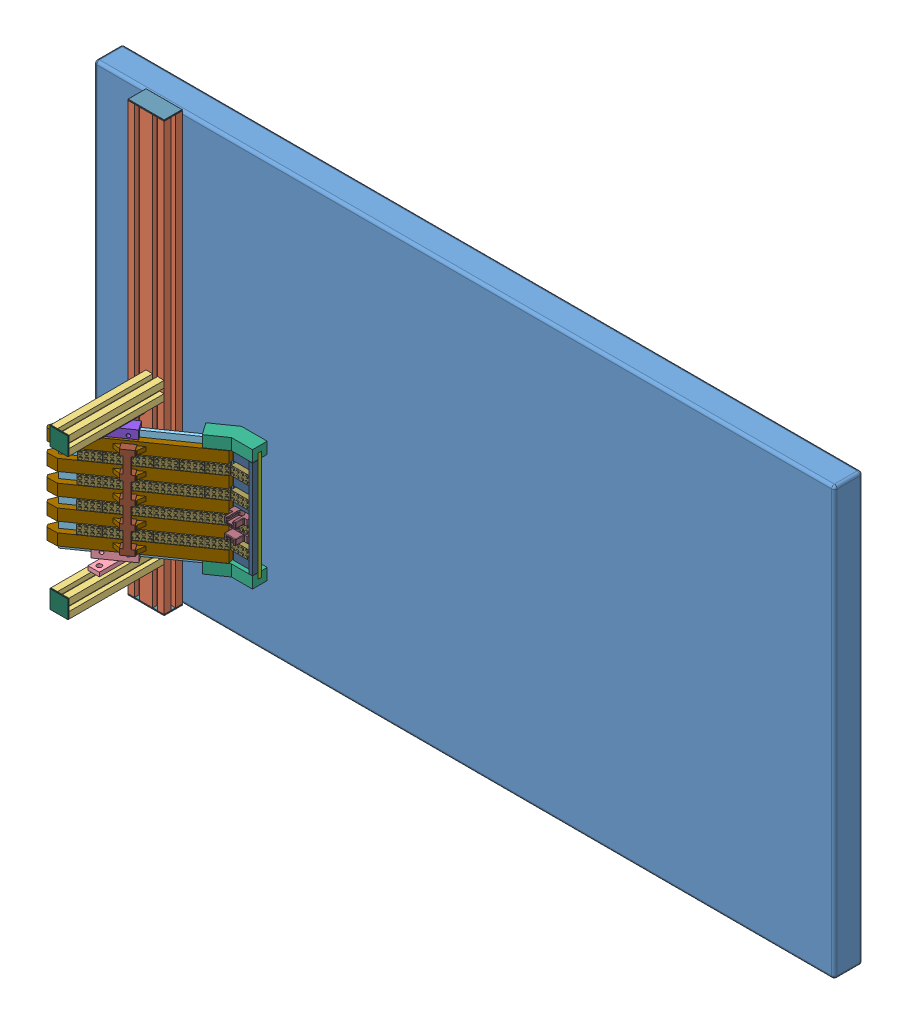
SolidWorks assembly Magazin_komplett, configuration Standard. Lengths in mm.
Overall size (1300 754 250.8).
54 component instances, 16 part files, 118 mates.
Components (placement in the parent):
- Tischplatte-1: Tischplatte [Standard] at (82.6175 27.9833 1300) size (1300 750 50)
- Bosch_Schiene-1: Bosch_Schiene [Standard] at (-444.1514 -347.0167 1381.8) x (1 0 0) z (0 1 0) size (63.6 31.8 750)
- Stützpfeiler-1: Stützpfeiler [Standard] at (-444.1514 -270.5414 1381.8) size (31.8 31.8 167)
- Adapter_Stütze_Magazin-1: Adapter_Stütze_Magazin [Standard] at (-438.2514 -238.7414 1489.7538) x (1 0 0) z (0 1 0) size (60.62 80 22)
- Holzplatte-1: Holzplatte [Standard] at (-485.6098 -226.7414 1493.64) x (0 1 0) z (-0.819152 0 0.573576) size (192 6 220)
- Winkel-1: Winkel [Standard] at (-273.1782 -226.7414 1360) x (-1 0 0) z (0 1 0) size (81.89 47.03 20)
- Holzplatte_kurz-1: Holzplatte_kurz [Standard] at (-303.1782 -226.7414 1365.9) x (0 1 0) z (-1 0 0) size (192 6 40)
- Winkel-2: Winkel [Standard] at (-331.1369 -34.7414 1378.2743) x (0.819152 0 -0.573576) z (0 -1 0) size (81.89 47.03 20)
- Adapter_Stütze_Magazin_gespiegelt-1: Adapter_Stütze_Magazin_gespiegelt [Standard] at (-438.2514 -22.7414 1409.8759) x (1 0 0) z (0 -1 0) size (60.62 80 22)
- Stützpfeiler-2: Stützpfeiler [Standard] at (-444.1514 -22.7414 1381.8) size (31.8 31.8 167)
- Schienen-1: Schienen [Standard] at (-485.6098 -196.5447 1493.64) x (0.819152 0 -0.573576) z (-0.573576 0 -0.819152) size (235 20 37.9)
- Schienen-2: Schienen [Standard] at (-485.6098 -158.7447 1493.64) x (0.819152 0 -0.573576) z (-0.573576 0 -0.819152) size (235 20 37.9)
- Schienen-3: Schienen [Standard] at (-485.6098 -120.9447 1493.64) x (0.819152 0 -0.573576) z (-0.573576 0 -0.819152) size (235 20 37.9)
- Schienen-4: Schienen [Standard] at (-485.6098 -83.1447 1493.64) x (0.819152 0 -0.573576) z (-0.573576 0 -0.819152) size (235 20 37.9)
- Schienen-5: Schienen [Standard] at (-485.6098 -45.3447 1493.64) x (0.819152 0 -0.573576) z (-0.573576 0 -0.819152) size (235 20 37.9)
- Entnahme_Kamm-1: Entnahme_Kamm [Standard] at (-263.1782 -216.5447 1365.9) x (0 1 0) z (1 0 0) size (171.2 10 40)
- Abstandshalter-1: Abstandshalter [Standard] at (-390.0599 -51.2247 1455.0572) x (0 -1 0) z (0.819152 0 -0.573576) size (161.32 13.2 20)
- GreiferMitLegostein-1: GreiferMitLegostein [Standard] at (-275.4934 -166.3532 1407.2912) x (0 0 -1) z (0 1 0) size (27.6 32 35.8)
  - Legostein-1: Legostein [Standard] at (41.3912 -5.9152 7.6084) x (0 1 0) z (0 0 1) size (31.8 11.4 15.8)
  - Greifbacken-2: Greifbacken [Standard] at (13.7912 20.1083 33.4084) x (1 0 0) z (0 0 -1) size (25.5 32 13.51) (hidden)
  - Greifbacken-3: Greifbacken [Standard] at (13.7912 -0.0917 -2.3916) size (25.5 32 13.51) (hidden)
  - Greifbacken_HSHL-1: Greifbacken_HSHL [Standard] at (13.7912 -0.2152 -2.3916) size (24.5 32 13.51)
  - Greifbacken_HSHL-2: Greifbacken_HSHL [Standard] at (13.7912 19.9848 33.4084) x (1 0 0) z (0 0 -1) size (24.5 32 13.51)
- Legostein-2: Legostein [Standard] at (-269.5782 -196.5447 1365.9) x (-1 0 0) z (0 1 0) size (31.8 11.4 15.8)
- Legostein-4: Legostein [Standard] at (-269.5782 -120.9447 1365.9) x (-1 0 0) z (0 1 0) size (31.8 11.4 15.8)
- Legostein-5: Legostein [Standard] at (-269.5782 -83.1447 1365.9) x (-1 0 0) z (0 1 0) size (31.8 11.4 15.8)
- Legostein-6: Legostein [Standard] at (-360.206 -196.5447 1405.8313) x (-0.819152 0 0.573576) z (0 1 0) size (31.8 11.4 15.8)
- Legostein-7: Legostein [Standard] at (-439.6163 -196.5447 1461.435) x (-0.819152 0 0.573576) z (0 1 0) size (31.8 11.4 15.8)
- Legostein-8: Legostein [Standard] at (-386.6114 -196.5447 1424.3206) x (-0.819152 0 0.573576) z (0 1 0) size (31.8 11.4 15.8)
- Legostein-9: Legostein [Standard] at (-307.4942 -196.5447 1368.9221) x (-0.819152 0 0.573576) z (0 1 0) size (31.8 11.4 15.8)
- Legostein-10: Legostein [Standard] at (-413.1818 -196.5447 1442.9253) x (-0.819152 0 0.573576) z (0 1 0) size (31.8 11.4 15.8)
- Legostein-11: Legostein [Standard] at (-333.8754 -196.5447 1387.3944) x (-0.819152 0 0.573576) z (0 1 0) size (31.8 11.4 15.8)
- Legostein-12: Legostein [Standard] at (-307.4185 -158.7447 1368.8691) x (-0.819152 0 0.573576) z (0 1 0) size (31.8 11.4 15.8)
- Legostein-13: Legostein [Standard] at (-333.8419 -158.7447 1387.371) x (-0.819152 0 0.573576) z (0 1 0) size (31.8 11.4 15.8)
- Legostein-14: Legostein [Standard] at (-360.1564 -158.7447 1405.7966) x (-0.819152 0 0.573576) z (0 1 0) size (31.8 11.4 15.8)
- Legostein-15: Legostein [Standard] at (-386.5305 -158.7447 1424.2639) x (-0.819152 0 0.573576) z (0 1 0) size (31.8 11.4 15.8)
- Legostein-16: Legostein [Standard] at (-413.0944 -158.7447 1442.8642) x (-0.819152 0 0.573576) z (0 1 0) size (31.8 11.4 15.8)
- Legostein-17: Legostein [Standard] at (-439.591 -158.7447 1461.4173) x (-0.819152 0 0.573576) z (0 1 0) size (31.8 11.4 15.8)
- Legostein-18: Legostein [Standard] at (-439.252 -120.9447 1461.1799) x (-0.819152 0 0.573576) z (0 1 0) size (31.8 11.4 15.8)
- Legostein-19: Legostein [Standard] at (-412.8102 -120.9447 1442.6651) x (-0.819152 0 0.573576) z (0 1 0) size (31.8 11.4 15.8)
- Legostein-20: Legostein [Standard] at (-386.5116 -120.9447 1424.2507) x (-0.819152 0 0.573576) z (0 1 0) size (31.8 11.4 15.8)
- Legostein-21: Legostein [Standard] at (-360.154 -120.9447 1405.7949) x (-0.819152 0 0.573576) z (0 1 0) size (31.8 11.4 15.8)
- Legostein-22: Legostein [Standard] at (-333.7719 -120.9447 1387.3219) x (-0.819152 0 0.573576) z (0 1 0) size (31.8 11.4 15.8)
- Legostein-23: Legostein [Standard] at (-307.3652 -120.9447 1368.8318) x (-0.819152 0 0.573576) z (0 1 0) size (31.8 11.4 15.8)
- Legostein-24: Legostein [Standard] at (-307.2324 -83.1447 1368.7388) x (-0.819152 0 0.573576) z (0 1 0) size (31.8 11.4 15.8)
- Legostein-25: Legostein [Standard] at (-412.5918 -83.1447 1442.5123) x (-0.819152 0 0.573576) z (0 1 0) size (31.8 11.4 15.8)
- Legostein-26: Legostein [Standard] at (-386.1974 -83.1447 1424.0307) x (-0.819152 0 0.573576) z (0 1 0) size (31.8 11.4 15.8)
- Legostein-27: Legostein [Standard] at (-359.8901 -83.1447 1405.6101) x (-0.819152 0 0.573576) z (0 1 0) size (31.8 11.4 15.8)
- Legostein-28: Legostein [Standard] at (-333.5713 -83.1447 1387.1815) x (-0.819152 0 0.573576) z (0 1 0) size (31.8 11.4 15.8)
- Legostein-29: Legostein [Standard] at (-438.9743 -83.1447 1460.9854) x (-0.819152 0 0.573576) z (0 1 0) size (31.8 11.4 15.8)
- Abdeckung_Breit-1: Abdeckung_Breit [Standard] at (-444.1514 -349.0167 1365.9) x (1 0 0) z (0 1 0) size (63.6 31.8 2)
- Abdeckung_Breit-2: Abdeckung_Breit [Standard] at (-444.1514 402.9833 1365.9) x (1 0 0) z (0 1 0) size (63.6 31.8 2)
- Abdeckung_quadratisch-1: Abdeckung_quadratisch [Standard] at (-428.2514 -254.6414 1548.8) size (31.8 31.8 2)
- Abdeckung_quadratisch-2: Abdeckung_quadratisch [Standard] at (-428.2514 -6.8414 1548.8) size (31.8 31.8 2)
Mates (geometry in assembly coordinates):
- Deckungsgleich1: coincident anti-aligned: plane of Tischplatte-1 through (82.6175 27.9833 1350) normal (0 0 1); plane of Bosch_Schiene-1 through (-444.1514 402.9833 1350) normal (0 0 -1)
- Deckungsgleich2: coincident aligned: plane of Tischplatte-1 through (-567.3825 402.9833 1350) normal (0 1 0); plane of Bosch_Schiene-1 through (-444.1514 402.9833 1381.8) normal (0 1 0)
- Deckungsgleich3: coincident anti-aligned: plane of Bosch_Schiene-1 through (-444.1514 402.9833 1381.8) normal (0 0 1); plane of Stützpfeiler-1 through (-444.1514 -270.5414 1381.8) normal (0 0 -1)
- Parallel1: parallel aligned: line of Bosch_Schiene-1 through (-432.5514 -347.0167 1374) axis (1 0 0); line of Stützpfeiler-1 through (-432.5514 -262.7414 1381.8) axis (1 0 0)
- Deckungsgleich6: coincident anti-aligned: line of Bosch_Schiene-1 through (-412.3514 402.9833 1381.8) axis (0 -1 0); line of Stützpfeiler-1 through (-412.3514 -270.5414 1381.8) axis (0 1 0)
- Deckungsgleich7: coincident anti-aligned: plane of Stützpfeiler-1 through (-444.1514 -238.7414 1548.8) normal (0 1 0); plane of Adapter_Stütze_Magazin-1 through (-438.2514 -238.7414 1489.7538) normal (0 -1 0)
- Tangential1: tangent anti-aligned: plane of Stützpfeiler-1 through (-432.5514 -238.7414 1548.8) normal (1 0 0); cylinder of Adapter_Stütze_Magazin-1 through (-428.2514 -231.7414 1479.7538) axis (0 -1 0) radius 4.3
- Tangential2: tangent anti-aligned: plane of Stützpfeiler-1 through (-432.5514 -238.7414 1548.8) normal (1 0 0); cylinder of Adapter_Stütze_Magazin-1 through (-428.2514 -231.7414 1419.7538) axis (0 -1 0) radius 4.3
- Deckungsgleich9: coincident anti-aligned: plane of Adapter_Stütze_Magazin-1 through (-438.2514 -226.7414 1489.7538) normal (0 1 0); plane of Holzplatte-1 through (-489.0512 -226.7414 1488.725) normal (0 -1 0)
- Deckungsgleich10: coincident anti-aligned: plane of Adapter_Stütze_Magazin-1 through (-405.3689 -226.7414 1430.13) normal (0.573576 0 0.819152); plane of Holzplatte-1 through (-489.0512 -226.7414 1488.725) normal (-0.573576 0 -0.819152)
- Deckungsgleich11: coincident anti-aligned: plane of Holzplatte-1 through (-489.0512 -226.7414 1488.725) normal (0 -1 0); plane of Winkel-1 through (-273.1782 -226.7414 1360) normal (0 1 0)
- Deckungsgleich12: coincident anti-aligned: plane of Holzplatte-1 through (-485.6098 -226.7414 1493.64) normal (0.573576 0 0.819152); plane of Winkel-1 through (-280.2758 -216.7414 1349.8636) normal (-0.573576 0 -0.819152)
- Deckungsgleich13: coincident anti-aligned: plane of Winkel-1 through (-273.1782 -226.7414 1360) normal (0 1 0); plane of Holzplatte_kurz-1 through (-303.1782 -226.7414 1359.9) normal (0 -1 0)
- Deckungsgleich14: coincident anti-aligned: plane of Winkel-1 through (-273.1782 -216.7414 1365.9) normal (0 0 -1); plane of Holzplatte_kurz-1 through (-303.1782 -226.7414 1365.9) normal (0 0 1)
- Deckungsgleich15: coincident aligned: plane of Winkel-1 through (-263.1782 -216.7414 1360) normal (1 0 0); plane of Holzplatte_kurz-1 through (-263.1782 -226.7414 1359.9) normal (1 0 0)
- Deckungsgleich16: coincident anti-aligned: plane of Holzplatte-1 through (-489.0512 -34.7414 1488.725) normal (0 1 0); plane of Winkel-2 through (-331.1369 -34.7414 1378.2743) normal (0 -1 0)
- Deckungsgleich17: coincident anti-aligned: plane of Holzplatte-1 through (-485.6098 -226.7414 1493.64) normal (0.573576 0 0.819152); plane of Winkel-2 through (-327.7528 -44.7414 1383.1073) normal (-0.573576 0 -0.819152)
- Deckungsgleich18: coincident anti-aligned: plane of Holzplatte_kurz-1 through (-303.1782 -226.7414 1365.9) normal (0 0 1); plane of Winkel-2 through (-331.1369 -44.7414 1365.9) normal (0 0 -1)
- Deckungsgleich19: coincident anti-aligned: plane of Tischplatte-1 through (82.6175 27.9833 1350) normal (0 0 1); plane of Winkel-1 through (-273.1782 -236.7414 1350) normal (0 0 -1)
- Deckungsgleich20: coincident anti-aligned: plane of Holzplatte-1 through (-489.0512 -34.7414 1488.725) normal (0 1 0); plane of Adapter_Stütze_Magazin_gespiegelt-1 through (-438.2514 -34.7414 1409.8759) normal (0 -1 0)
- Deckungsgleich21: coincident anti-aligned: plane of Holzplatte-1 through (-485.6098 -226.7414 1493.64) normal (0.573576 0 0.819152); plane of Adapter_Stütze_Magazin_gespiegelt-1 through (-401.9848 -34.7414 1435.0851) normal (-0.573576 0 -0.819152)
- Deckungsgleich22: coincident aligned: plane of Adapter_Stütze_Magazin-1 through (-418.2514 -231.7414 1489.7538) normal (1 0 0); plane of Adapter_Stütze_Magazin_gespiegelt-1 through (-418.2514 -29.7414 1409.8759) normal (1 0 0)
- Deckungsgleich23: coincident anti-aligned: plane of Bosch_Schiene-1 through (-444.1514 402.9833 1381.8) normal (0 0 1); plane of Stützpfeiler-2 through (-444.1514 -22.7414 1381.8) normal (0 0 -1)
- Deckungsgleich24: coincident aligned: plane of Bosch_Schiene-1 through (-412.3514 402.9833 1381.8) normal (1 0 0); plane of Stützpfeiler-2 through (-412.3514 -11.1414 1548.8) normal (1 0 0)
- Deckungsgleich25: coincident anti-aligned: plane of Adapter_Stütze_Magazin_gespiegelt-1 through (-438.2514 -22.7414 1409.8759) normal (0 1 0); plane of Stützpfeiler-2 through (-423.9514 -22.7414 1548.8) normal (0 -1 0)
- Deckungsgleich26: coincident anti-aligned: plane of Holzplatte-1 through (-485.6098 -226.7414 1493.64) normal (0.573576 0 0.819152); plane of Schienen-1 through (-485.6098 -216.5447 1493.64) normal (-0.573576 0 -0.819152)
- Deckungsgleich27: coincident anti-aligned: plane of Holzplatte-1 through (-489.0512 -226.7414 1488.725) normal (-0.819152 0 0.573576); plane of Schienen-1 through (-485.6098 -216.5447 1493.64) normal (0.819152 0 -0.573576)
- Deckungsgleich28: coincident anti-aligned: plane of Holzplatte-1 through (-485.6098 -226.7414 1493.64) normal (0.573576 0 0.819152); plane of Schienen-2 through (-485.6098 -178.7447 1493.64) normal (-0.573576 0 -0.819152)
- Deckungsgleich29: coincident anti-aligned: plane of Holzplatte-1 through (-485.6098 -226.7414 1493.64) normal (0.573576 0 0.819152); plane of Schienen-3 through (-485.6098 -140.9447 1493.64) normal (-0.573576 0 -0.819152)
- Deckungsgleich30: coincident anti-aligned: plane of Holzplatte-1 through (-485.6098 -226.7414 1493.64) normal (0.573576 0 0.819152); plane of Schienen-4 through (-485.6098 -103.1447 1493.64) normal (-0.573576 0 -0.819152)
- Deckungsgleich31: coincident anti-aligned: plane of Holzplatte-1 through (-485.6098 -226.7414 1493.64) normal (0.573576 0 0.819152); plane of Schienen-5 through (-485.6098 -65.3447 1493.64) normal (-0.573576 0 -0.819152)
- Deckungsgleich32: coincident anti-aligned: plane of Holzplatte-1 through (-489.0512 -226.7414 1488.725) normal (-0.819152 0 0.573576); plane of Schienen-2 through (-485.6098 -178.7447 1493.64) normal (0.819152 0 -0.573576)
- Deckungsgleich33: coincident anti-aligned: plane of Holzplatte-1 through (-489.0512 -226.7414 1488.725) normal (-0.819152 0 0.573576); plane of Schienen-3 through (-485.6098 -140.9447 1493.64) normal (0.819152 0 -0.573576)
- Deckungsgleich34: coincident anti-aligned: plane of Holzplatte-1 through (-489.0512 -226.7414 1488.725) normal (-0.819152 0 0.573576); plane of Schienen-4 through (-485.6098 -103.1447 1493.64) normal (0.819152 0 -0.573576)
- Deckungsgleich35: coincident anti-aligned: plane of Holzplatte-1 through (-489.0512 -226.7414 1488.725) normal (-0.819152 0 0.573576); plane of Schienen-5 through (-485.6098 -65.3447 1493.64) normal (0.819152 0 -0.573576)
- Deckungsgleich36: coincident anti-aligned: plane of Holzplatte_kurz-1 through (-303.1782 -226.7414 1365.9) normal (0 0 1); plane of Entnahme_Kamm-1 through (-263.1782 -216.5447 1365.9) normal (0 0 -1)
- Deckungsgleich37: coincident aligned: plane of Holzplatte_kurz-1 through (-263.1782 -226.7414 1359.9) normal (1 0 0); plane of Entnahme_Kamm-1 through (-263.1782 -216.5447 1368.9) normal (1 0 0)
- Deckungsgleich43: coincident aligned: plane of Schienen-1 through (-485.6098 -196.5447 1493.64) normal (0 1 0); plane of Entnahme_Kamm-1 through (-263.1782 -196.5447 1368.9) normal (0 1 0)
- Deckungsgleich44: coincident anti-aligned: plane of Schienen-1 through (-474.1382 -216.5447 1510.023) normal (0.573576 0 0.819152); plane of Abstandshalter-1 through (-391.8954 -51.2247 1452.4359) normal (-0.573576 0 -0.819152)
- Deckungsgleich45: coincident anti-aligned: plane of Schienen-1 through (-390.7482 -210.1447 1454.0742) normal (-0.819152 0 0.573576); plane of Abstandshalter-1 through (-391.8954 -51.2247 1452.4359) normal (0.819152 0 -0.573576)
- Deckungsgleich46: coincident anti-aligned: plane of Schienen-1 through (-485.6098 -210.1447 1493.64) normal (0 -1 0); plane of Abstandshalter-1 through (-397.6311 -210.1447 1444.2444) normal (0 1 0)
- Deckungsgleich47: coincident anti-aligned: plane of Schienen-2 through (-485.6098 -172.3447 1493.64) normal (0 -1 0); plane of Abstandshalter-1 through (-397.6311 -172.3447 1444.2444) normal (0 1 0)
- Deckungsgleich48: coincident anti-aligned: plane of Schienen-3 through (-485.6098 -134.5447 1493.64) normal (0 -1 0); plane of Abstandshalter-1 through (-397.6311 -134.5447 1444.2444) normal (0 1 0)
- Deckungsgleich49: coincident anti-aligned: plane of Schienen-4 through (-485.6098 -96.7447 1493.64) normal (0 -1 0); plane of Abstandshalter-1 through (-414.0142 -96.7447 1455.7159) normal (0 1 0)
- Deckungsgleich50: coincident anti-aligned: plane of Schienen-5 through (-485.6098 -58.9447 1493.64) normal (0 -1 0); plane of Abstandshalter-1 through (-397.6311 -58.9447 1444.2444) normal (0 1 0)
- Deckungsgleich51: coincident anti-aligned: plane of Holzplatte_kurz-1 through (-303.1782 -226.7414 1365.9) normal (0 0 1); plane of GreiferMitLegostein-1/Legostein-1 through (-269.5782 -142.9447 1365.9) normal (0 0 -1)
- Deckungsgleich52: coincident anti-aligned: plane of Entnahme_Kamm-1 through (-269.5782 -216.5447 1368.9) normal (-1 0 0); plane of GreiferMitLegostein-1/Legostein-1 through (-269.5782 -142.9447 1365.9) normal (1 0 0)
- Deckungsgleich53: coincident anti-aligned: plane of Entnahme_Kamm-1 through (-263.1782 -158.7447 1368.9) normal (0 1 0); plane of GreiferMitLegostein-1/Legostein-1 through (-269.5782 -158.7447 1365.9) normal (0 -1 0)
- Deckungsgleich54: coincident anti-aligned: plane of Holzplatte_kurz-1 through (-303.1782 -226.7414 1365.9) normal (0 0 1); plane of Legostein-2 through (-269.5782 -180.7447 1365.9) normal (0 0 -1)
- Deckungsgleich55: coincident anti-aligned: plane of Entnahme_Kamm-1 through (-269.5782 -216.5447 1368.9) normal (-1 0 0); plane of Legostein-2 through (-269.5782 -180.7447 1365.9) normal (1 0 0)
- Deckungsgleich56: coincident anti-aligned: plane of Entnahme_Kamm-1 through (-263.1782 -196.5447 1368.9) normal (0 1 0); plane of Legostein-2 through (-269.5782 -196.5447 1365.9) normal (0 -1 0)
- Deckungsgleich57: coincident anti-aligned: plane of Holzplatte_kurz-1 through (-303.1782 -226.7414 1365.9) normal (0 0 1); plane of Legostein-4 through (-269.5782 -105.1447 1365.9) normal (0 0 -1)
- Deckungsgleich58: coincident anti-aligned: plane of Entnahme_Kamm-1 through (-269.5782 -216.5447 1368.9) normal (-1 0 0); plane of Legostein-4 through (-269.5782 -105.1447 1365.9) normal (1 0 0)
- Deckungsgleich59: coincident anti-aligned: plane of Entnahme_Kamm-1 through (-263.1782 -120.9447 1368.9) normal (0 1 0); plane of Legostein-4 through (-269.5782 -120.9447 1365.9) normal (0 -1 0)
- Deckungsgleich60: coincident anti-aligned: plane of Holzplatte_kurz-1 through (-303.1782 -226.7414 1365.9) normal (0 0 1); plane of Legostein-5 through (-269.5782 -67.3447 1365.9) normal (0 0 -1)
- Deckungsgleich61: coincident anti-aligned: plane of Entnahme_Kamm-1 through (-263.1782 -83.1447 1368.9) normal (0 1 0); plane of Legostein-5 through (-269.5782 -83.1447 1365.9) normal (0 -1 0)
- Deckungsgleich62: coincident anti-aligned: plane of Entnahme_Kamm-1 through (-269.5782 -216.5447 1368.9) normal (-1 0 0); plane of Legostein-5 through (-269.5782 -67.3447 1365.9) normal (1 0 0)
- Deckungsgleich63: coincident aligned: plane of Legostein-6 through (-360.206 -180.7447 1405.8313) normal (-0.573576 0 -0.819152); plane of Legostein-7 through (-439.6163 -180.7447 1461.435) normal (-0.573576 0 -0.819152)
- Deckungsgleich64: coincident aligned: plane of Legostein-6 through (-360.206 -180.7447 1405.8313) normal (-0.573576 0 -0.819152); plane of Legostein-7 through (-439.6163 -180.7447 1461.435) normal (-0.573576 0 -0.819152)
- Deckungsgleich65: coincident aligned: plane of Legostein-7 through (-439.6163 -180.7447 1461.435) normal (-0.573576 0 -0.819152); plane of Legostein-8 through (-386.6114 -180.7447 1424.3206) normal (-0.573576 0 -0.819152)
- Deckungsgleich66: coincident aligned: plane of Legostein-8 through (-386.6114 -180.7447 1424.3206) normal (-0.573576 0 -0.819152); plane of Legostein-9 through (-307.4942 -180.7447 1368.9221) normal (-0.573576 0 -0.819152)
- Deckungsgleich67: coincident aligned: plane of Legostein-9 through (-307.4942 -180.7447 1368.9221) normal (-0.573576 0 -0.819152); plane of Legostein-10 through (-413.1818 -180.7447 1442.9253) normal (-0.573576 0 -0.819152)
- Deckungsgleich68: coincident aligned: plane of Legostein-10 through (-413.1818 -180.7447 1442.9253) normal (-0.573576 0 -0.819152); plane of Legostein-11 through (-333.8754 -180.7447 1387.3944) normal (-0.573576 0 -0.819152)
- Deckungsgleich69: coincident anti-aligned: plane of Holzplatte-1 through (-485.6098 -226.7414 1493.64) normal (0.573576 0 0.819152); plane of Legostein-6 through (-360.206 -180.7447 1405.8313) normal (-0.573576 0 -0.819152)
- Deckungsgleich70: coincident aligned: plane of Legostein-6 through (-360.206 -196.5447 1405.8313) normal (0 -1 0); plane of Legostein-11 through (-333.8754 -196.5447 1387.3944) normal (0 -1 0)
- Deckungsgleich71: coincident aligned: plane of Legostein-6 through (-360.206 -196.5447 1405.8313) normal (0 -1 0); plane of Legostein-10 through (-413.1818 -196.5447 1442.9253) normal (0 -1 0)
- Deckungsgleich72: coincident aligned: plane of Legostein-9 through (-307.4942 -196.5447 1368.9221) normal (0 -1 0); plane of Legostein-10 through (-413.1818 -196.5447 1442.9253) normal (0 -1 0)
- Deckungsgleich73: coincident aligned: plane of Legostein-8 through (-386.6114 -196.5447 1424.3206) normal (0 -1 0); plane of Legostein-11 through (-333.8754 -196.5447 1387.3944) normal (0 -1 0)
- Deckungsgleich74: coincident aligned: plane of Legostein-7 through (-439.6163 -196.5447 1461.435) normal (0 -1 0); plane of Legostein-10 through (-413.1818 -196.5447 1442.9253) normal (0 -1 0)
- Deckungsgleich75: coincident anti-aligned: plane of Schienen-1 through (-485.6098 -196.5447 1493.64) normal (0 1 0); plane of Legostein-9 through (-307.4942 -196.5447 1368.9221) normal (0 -1 0)
- Deckungsgleich76: coincident aligned: plane of Legostein-16 through (-413.0944 -142.9447 1442.8642) normal (-0.573576 0 -0.819152); plane of Legostein-17 through (-439.591 -142.9447 1461.4173) normal (-0.573576 0 -0.819152)
- Deckungsgleich77: coincident aligned: plane of Legostein-15 through (-386.5305 -142.9447 1424.2639) normal (-0.573576 0 -0.819152); plane of Legostein-16 through (-413.0944 -142.9447 1442.8642) normal (-0.573576 0 -0.819152)
- Deckungsgleich78: coincident aligned: plane of Legostein-14 through (-360.1564 -142.9447 1405.7966) normal (-0.573576 0 -0.819152); plane of Legostein-15 through (-386.5305 -142.9447 1424.2639) normal (-0.573576 0 -0.819152)
- Deckungsgleich79: coincident aligned: plane of Legostein-13 through (-333.8419 -142.9447 1387.371) normal (-0.573576 0 -0.819152); plane of Legostein-14 through (-360.1564 -142.9447 1405.7966) normal (-0.573576 0 -0.819152)
- Deckungsgleich80: coincident aligned: plane of Legostein-12 through (-307.4185 -142.9447 1368.8691) normal (-0.573576 0 -0.819152); plane of Legostein-13 through (-333.8419 -142.9447 1387.371) normal (-0.573576 0 -0.819152)
- Deckungsgleich81: coincident aligned: plane of Legostein-12 through (-307.4185 -158.7447 1368.8691) normal (0 -1 0); plane of Legostein-13 through (-333.8419 -158.7447 1387.371) normal (0 -1 0)
- Deckungsgleich82: coincident aligned: plane of Legostein-13 through (-333.8419 -158.7447 1387.371) normal (0 -1 0); plane of Legostein-14 through (-360.1564 -158.7447 1405.7966) normal (0 -1 0)
- Deckungsgleich83: coincident aligned: plane of Legostein-14 through (-360.1564 -158.7447 1405.7966) normal (0 -1 0); plane of Legostein-15 through (-386.5305 -158.7447 1424.2639) normal (0 -1 0)
- Deckungsgleich84: coincident aligned: plane of Legostein-15 through (-386.5305 -158.7447 1424.2639) normal (0 -1 0); plane of Legostein-16 through (-413.0944 -158.7447 1442.8642) normal (0 -1 0)
- Deckungsgleich85: coincident aligned: plane of Legostein-16 through (-413.0944 -158.7447 1442.8642) normal (0 -1 0); plane of Legostein-17 through (-439.591 -158.7447 1461.4173) normal (0 -1 0)
- Deckungsgleich86: coincident anti-aligned: plane of Holzplatte-1 through (-485.6098 -226.7414 1493.64) normal (0.573576 0 0.819152); plane of Legostein-12 through (-307.4185 -142.9447 1368.8691) normal (-0.573576 0 -0.819152)
- Deckungsgleich87: coincident anti-aligned: plane of Schienen-2 through (-485.6098 -158.7447 1493.64) normal (0 1 0); plane of Legostein-12 through (-307.4185 -158.7447 1368.8691) normal (0 -1 0)
- Deckungsgleich88: coincident aligned: plane of Legostein-22 through (-333.7719 -105.1447 1387.3219) normal (-0.573576 0 -0.819152); plane of Legostein-23 through (-307.3652 -105.1447 1368.8318) normal (-0.573576 0 -0.819152)
- Deckungsgleich89: coincident aligned: plane of Legostein-21 through (-360.154 -105.1447 1405.7949) normal (-0.573576 0 -0.819152); plane of Legostein-22 through (-333.7719 -105.1447 1387.3219) normal (-0.573576 0 -0.819152)
- Deckungsgleich90: coincident aligned: plane of Legostein-20 through (-386.5116 -105.1447 1424.2507) normal (-0.573576 0 -0.819152); plane of Legostein-21 through (-360.154 -105.1447 1405.7949) normal (-0.573576 0 -0.819152)
- Deckungsgleich91: coincident aligned: plane of Legostein-19 through (-412.8102 -105.1447 1442.6651) normal (-0.573576 0 -0.819152); plane of Legostein-20 through (-386.5116 -105.1447 1424.2507) normal (-0.573576 0 -0.819152)
- Deckungsgleich92: coincident aligned: plane of Legostein-18 through (-439.252 -105.1447 1461.1799) normal (-0.573576 0 -0.819152); plane of Legostein-19 through (-412.8102 -105.1447 1442.6651) normal (-0.573576 0 -0.819152)
- Deckungsgleich93: coincident aligned: plane of Legostein-22 through (-333.7719 -120.9447 1387.3219) normal (0 -1 0); plane of Legostein-23 through (-307.3652 -120.9447 1368.8318) normal (0 -1 0)
- Deckungsgleich94: coincident aligned: plane of Legostein-21 through (-360.154 -120.9447 1405.7949) normal (0 -1 0); plane of Legostein-22 through (-333.7719 -120.9447 1387.3219) normal (0 -1 0)
- Deckungsgleich95: coincident aligned: plane of Legostein-20 through (-386.5116 -120.9447 1424.2507) normal (0 -1 0); plane of Legostein-21 through (-360.154 -120.9447 1405.7949) normal (0 -1 0)
- Deckungsgleich96: coincident aligned: plane of Legostein-19 through (-412.8102 -120.9447 1442.6651) normal (0 -1 0); plane of Legostein-20 through (-386.5116 -120.9447 1424.2507) normal (0 -1 0)
- Deckungsgleich97: coincident aligned: plane of Legostein-18 through (-439.252 -120.9447 1461.1799) normal (0 -1 0); plane of Legostein-19 through (-412.8102 -120.9447 1442.6651) normal (0 -1 0)
- Deckungsgleich98: coincident anti-aligned: plane of Schienen-3 through (-485.6098 -120.9447 1493.64) normal (0 1 0); plane of Legostein-23 through (-307.3652 -120.9447 1368.8318) normal (0 -1 0)
- Deckungsgleich99: coincident anti-aligned: plane of Holzplatte-1 through (-485.6098 -226.7414 1493.64) normal (0.573576 0 0.819152); plane of Legostein-23 through (-307.3652 -105.1447 1368.8318) normal (-0.573576 0 -0.819152)
- Deckungsgleich100: coincident aligned: plane of Legostein-27 through (-359.8901 -67.3447 1405.6101) normal (-0.573576 0 -0.819152); plane of Legostein-28 through (-333.5713 -67.3447 1387.1815) normal (-0.573576 0 -0.819152)
- Deckungsgleich101: coincident aligned: plane of Legostein-26 through (-386.1974 -67.3447 1424.0307) normal (-0.573576 0 -0.819152); plane of Legostein-27 through (-359.8901 -67.3447 1405.6101) normal (-0.573576 0 -0.819152)
- Deckungsgleich102: coincident aligned: plane of Legostein-25 through (-412.5918 -67.3447 1442.5123) normal (-0.573576 0 -0.819152); plane of Legostein-26 through (-386.1974 -67.3447 1424.0307) normal (-0.573576 0 -0.819152)
- Deckungsgleich103: coincident aligned: plane of Legostein-25 through (-412.5918 -67.3447 1442.5123) normal (-0.573576 0 -0.819152); plane of Legostein-29 through (-438.9743 -67.3447 1460.9854) normal (-0.573576 0 -0.819152)
- Deckungsgleich104: coincident aligned: plane of Legostein-24 through (-307.2324 -67.3447 1368.7388) normal (-0.573576 0 -0.819152); plane of Legostein-29 through (-438.9743 -67.3447 1460.9854) normal (-0.573576 0 -0.819152)
- Deckungsgleich105: coincident aligned: plane of Legostein-27 through (-359.8901 -83.1447 1405.6101) normal (0 -1 0); plane of Legostein-28 through (-333.5713 -83.1447 1387.1815) normal (0 -1 0)
- Deckungsgleich106: coincident aligned: plane of Legostein-26 through (-386.1974 -83.1447 1424.0307) normal (0 -1 0); plane of Legostein-27 through (-359.8901 -83.1447 1405.6101) normal (0 -1 0)
- Deckungsgleich107: coincident aligned: plane of Legostein-25 through (-412.5918 -83.1447 1442.5123) normal (0 -1 0); plane of Legostein-26 through (-386.1974 -83.1447 1424.0307) normal (0 -1 0)
- Deckungsgleich108: coincident aligned: plane of Legostein-25 through (-412.5918 -83.1447 1442.5123) normal (0 -1 0); plane of Legostein-29 through (-438.9743 -83.1447 1460.9854) normal (0 -1 0)
- Deckungsgleich109: coincident aligned: plane of Legostein-24 through (-307.2324 -83.1447 1368.7388) normal (0 -1 0); plane of Legostein-29 through (-438.9743 -83.1447 1460.9854) normal (0 -1 0)
- Deckungsgleich110: coincident anti-aligned: plane of Schienen-4 through (-485.6098 -83.1447 1493.64) normal (0 1 0); plane of Legostein-24 through (-307.2324 -83.1447 1368.7388) normal (0 -1 0)
- Deckungsgleich111: coincident anti-aligned: plane of Holzplatte-1 through (-485.6098 -226.7414 1493.64) normal (0.573576 0 0.819152); plane of Legostein-24 through (-307.2324 -67.3447 1368.7388) normal (-0.573576 0 -0.819152)
- Deckungsgleich113: coincident aligned: plane of Bosch_Schiene-1 through (-444.1514 402.9833 1381.8) normal (0 0 1); plane of Abdeckung_Breit-1 through (-475.9514 -347.0167 1381.8) normal (0 0 1)
- Deckungsgleich114: coincident aligned: plane of Bosch_Schiene-1 through (-412.3514 402.9833 1381.8) normal (1 0 0); plane of Abdeckung_Breit-1 through (-412.3514 -347.0167 1381.8) normal (1 0 0)
- Deckungsgleich115: coincident anti-aligned: plane of Bosch_Schiene-1 through (-444.1514 402.9833 1381.8) normal (0 1 0); plane of Abdeckung_Breit-2 through (-444.1514 402.9833 1365.9) normal (0 -1 0)
- Deckungsgleich116: coincident aligned: plane of Bosch_Schiene-1 through (-444.1514 402.9833 1381.8) normal (0 0 1); plane of Abdeckung_Breit-2 through (-475.9514 404.9833 1381.8) normal (0 0 1)
- Deckungsgleich117: coincident aligned: plane of Bosch_Schiene-1 through (-412.3514 402.9833 1381.8) normal (1 0 0); plane of Abdeckung_Breit-2 through (-412.3514 404.9833 1381.8) normal (1 0 0)
- Deckungsgleich118: coincident anti-aligned: plane of Bosch_Schiene-1 through (-444.1514 -347.0167 1381.8) normal (0 -1 0); plane of Abdeckung_Breit-1 through (-444.1514 -347.0167 1365.9) normal (0 1 0)
- Deckungsgleich119: coincident anti-aligned: plane of Stützpfeiler-1 through (-444.1514 -270.5414 1548.8) normal (0 0 1); plane of Abdeckung_quadratisch-1 through (-428.2514 -254.6414 1548.8) normal (0 0 -1)
- Deckungsgleich120: coincident aligned: plane of Stützpfeiler-1 through (-444.1514 -270.5414 1548.8) normal (0 -1 0); plane of Abdeckung_quadratisch-1 through (-444.1514 -270.5414 1550.8) normal (0 -1 0)
- Deckungsgleich121: coincident aligned: plane of Stützpfeiler-1 through (-412.3514 -258.9414 1548.8) normal (1 0 0); plane of Abdeckung_quadratisch-1 through (-412.3514 -270.5414 1550.8) normal (1 0 0)
- Deckungsgleich122: coincident anti-aligned: plane of Stützpfeiler-2 through (-444.1514 -22.7414 1548.8) normal (0 0 1); plane of Abdeckung_quadratisch-2 through (-428.2514 -6.8414 1548.8) normal (0 0 -1)
- Deckungsgleich123: coincident aligned: plane of Stützpfeiler-2 through (-412.3514 9.0586 1548.8) normal (1 0 0); plane of Abdeckung_quadratisch-2 through (-412.3514 -22.7414 1550.8) normal (1 0 0)
- Deckungsgleich124: coincident aligned: plane of Stützpfeiler-2 through (-444.1514 9.0586 1548.8) normal (0 1 0); plane of Abdeckung_quadratisch-2 through (-444.1514 9.0586 1550.8) normal (0 1 0)
